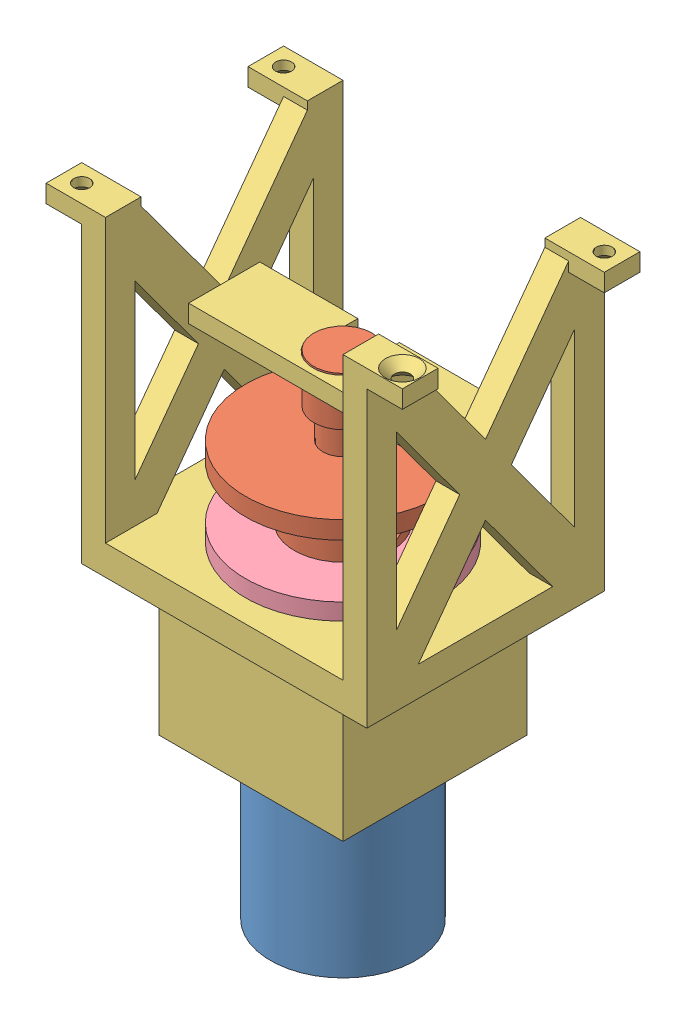
SolidWorks assembly Sestava1, configuration Výchozí. Lengths in mm.
Overall size (60 104.3 40).
4 component instances, 4 part files, 7 mates.
Components (placement in the parent):
- motor_with_gearbox-1: motor_with_gearbox [Výchozí] at (-28.6466 -26.9208 64.8) size (25 64.8 25)
- winch-1: winch [Výchozí] at (-28.6466 29.8792 64.8) size (32.8 28.2 32.8)
- winch_motor_holder-1: winch_motor_holder [Výchozí] at (-8.6466 26.8792 84.8) size (60 75.5 40)
- winch_cap-1: winch_cap [Výchozí] at (-28.6466 32.8792 64.8) x (0.999419 0 0.03407) z (0 -1 0) size (32.8 32.8 2.8)
Mates (geometry in assembly coordinates):
- Sjednocená1: coincident anti-aligned: plane of motor_with_gearbox-1 through (-16.1466 26.8792 64.8) normal (0 1 0); plane of winch_motor_holder-1 through (-8.6466 26.8792 84.8) normal (0 -1 0)
- Soustředná1: concentric aligned: circle of motor_with_gearbox-1; circle of winch_motor_holder-1
- Soustředná2: concentric aligned: circle of winch_motor_holder-1; circle of motor_with_gearbox-1
- Sjednocená2: coincident anti-aligned: plane of motor_with_gearbox-1 through (-26.6466 37.8792 64.8) normal (0 1 0); plane of winch-1 through (-28.6466 37.8792 64.8) normal (0 -1 0)
- Soustředná5: concentric aligned: cylinder of motor_with_gearbox-1 through (-28.6466 -26.9208 64.8) axis (0 -1 0) radius 2; cylinder of winch-1 through (-28.6466 37.8792 64.8) axis (0 -1 0) radius 2.2
- Soustředná6: concentric anti-aligned: cylinder of winch-1 through (-28.6466 29.8792 64.8) axis (0 -1 0) radius 5; cylinder of winch_cap-1 through (-28.6466 30.0792 64.8) axis (0 1 0) radius 5.2
- Tečná1: tangent: circle of winch-1; plane of winch_cap-1 through (-28.6466 32.8792 64.8) normal (0 1 0)
